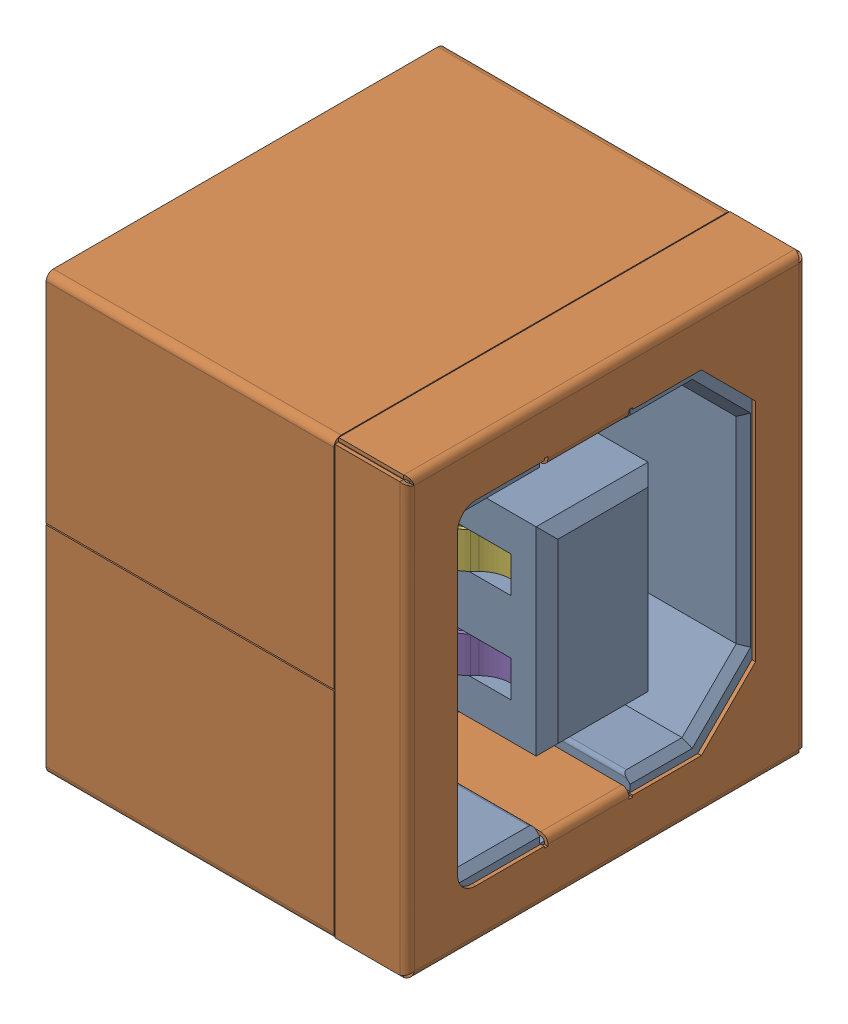
SolidWorks assembly USB_Type_B_Assembly1, configuration Default. Lengths in mm.
Overall size (13.3 12.05 11.05).
6 component instances, 3 part files, 0 mates.
Components (placement in the parent):
- USB_Type_B_Part3-1: USB_Type_B_Part3 [Default] at origin size (9.9 11.8 10.8)
- USB_Type_B_Part2-1: USB_Type_B_Part2 [Default] at (10 0 0) x (1 0 0) z (0 0 -1) size (10 12.05 11.05)
- USB_Type_B_Part4-1: USB_Type_B_Part4 [Default] at (-3.3 1.25 -1.05) x (0 1 0) z (0 0 -1) size (1 12.2 0.8)
- USB_Type_B_Part4-2: USB_Type_B_Part4 [Default] at (-3.3 -1.25 -1.05) x (0 1 0) z (0 0 -1) size (1 12.2 0.8)
- USB_Type_B_Part4-3: USB_Type_B_Part4 [Default] at (-3.3 -1.25 1.05) x (0 -1 0) z (0 0 1) size (1 12.2 0.8)
- USB_Type_B_Part4-4: USB_Type_B_Part4 [Default] at (-3.3 1.25 1.05) x (0 -1 0) z (0 0 1) size (1 12.2 0.8)
